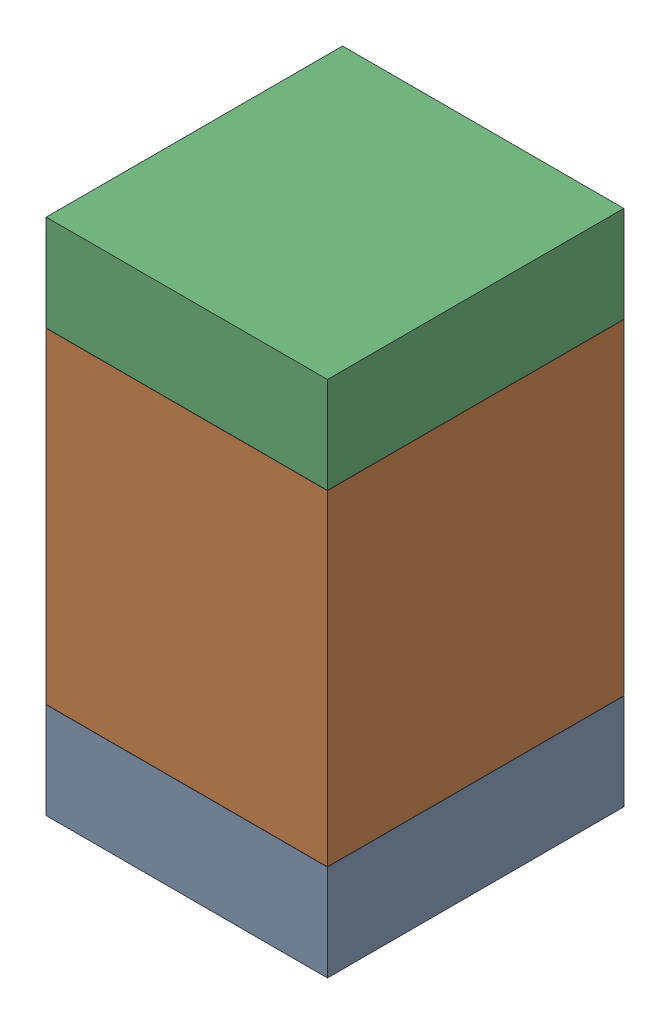
SolidWorks assembly R27, configuration Default. Lengths in mm.
Overall size (0.95 1.75 1).
6 component instances, 2 part files, 0 mates.
Components (placement in the parent):
- 6575495072-1: 6575495072 [Default] at (36.957 15.1625 0) size (0.95 0.32 1)
  - Extruded_6-1: Extruded_6 [Default] at origin size (0.95 0.32 1)
- 6575494912-1: 6575494912 [Default] at (36.957 15.875 0) size (0.95 1.1 1)
  - Extruded_7-1: Extruded_7 [Default] at origin size (0.95 1.1 1)
- 6575495072-2: 6575495072 [Default] at (36.957 16.5875 0) size (0.95 0.32 1)
  - Extruded_6-1: Extruded_6 [Default] at origin size (0.95 0.32 1)
